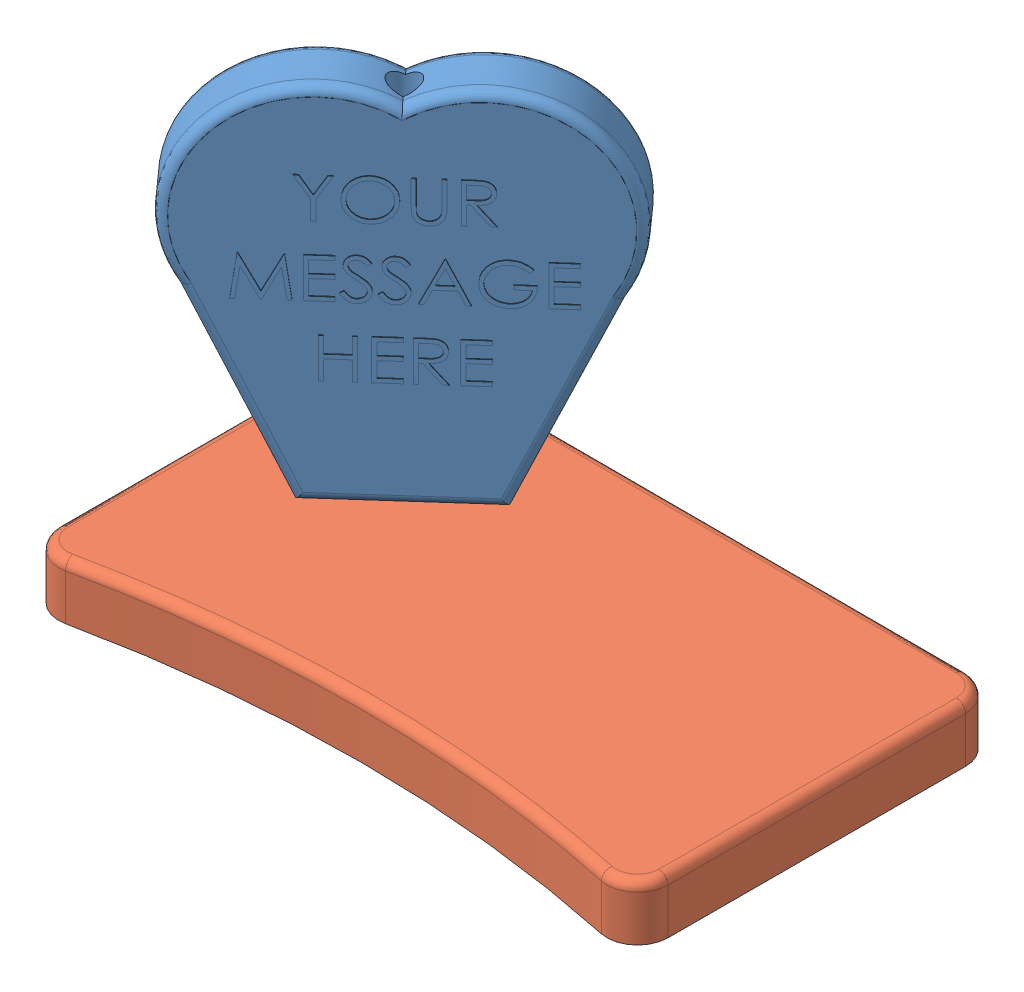
SolidWorks assembly Spokeshave Project Assembly, configuration Default. Lengths in mm.
Overall size (203.29 136.37 122.84).
3 component instances, 3 part files, 5 mates.
Components (placement in the parent):
- Heart-2: Heart [Default] at (268.3095 78 -64.6608) x (-0.746345 0 0.665559) z (-0.665559 0 -0.746345) size (114.98 118.37 18.46)
- Base-2: Base [Default] at (317.572 0 -52.195) x (0.999999 0 0.001098) z (-0.001098 0 0.999999) size (200 18 117.46)
- Dowel-1: Dowel [Default] at (263.3816 0 -72.3251) x (0.444783 0 -0.895638) z (0.895638 0 0.444783) size (6 38 6)
Mates (geometry in assembly coordinates):
- Concentric1: concentric aligned: cylinder of Heart-2 through (263.3816 38 -72.3251) axis (0 -1 0) radius 3; cylinder of Dowel-1 through (263.3816 38 -72.3251) axis (0 -1 0) radius 3
- Coincident4: coincident aligned: plane of Base-2 through (227.52 0 -4.831) normal (0 -1 0); plane of Dowel-1 through (263.3816 0 -72.3251) normal (0 -1 0)
- Coincident5: coincident anti-aligned: circle of Base-2; circle of Dowel-1
- Coincident6: coincident anti-aligned: plane of Heart-2 through (263.3816 38 -72.3251) normal (0 -1 0); plane of Dowel-1 through (263.3816 38 -72.3251) normal (0 1 0)
- Coincident11: coincident anti-aligned: plane of Base-2 through (227.52 0 -4.831) normal (0 -1 0); plane of assembly
